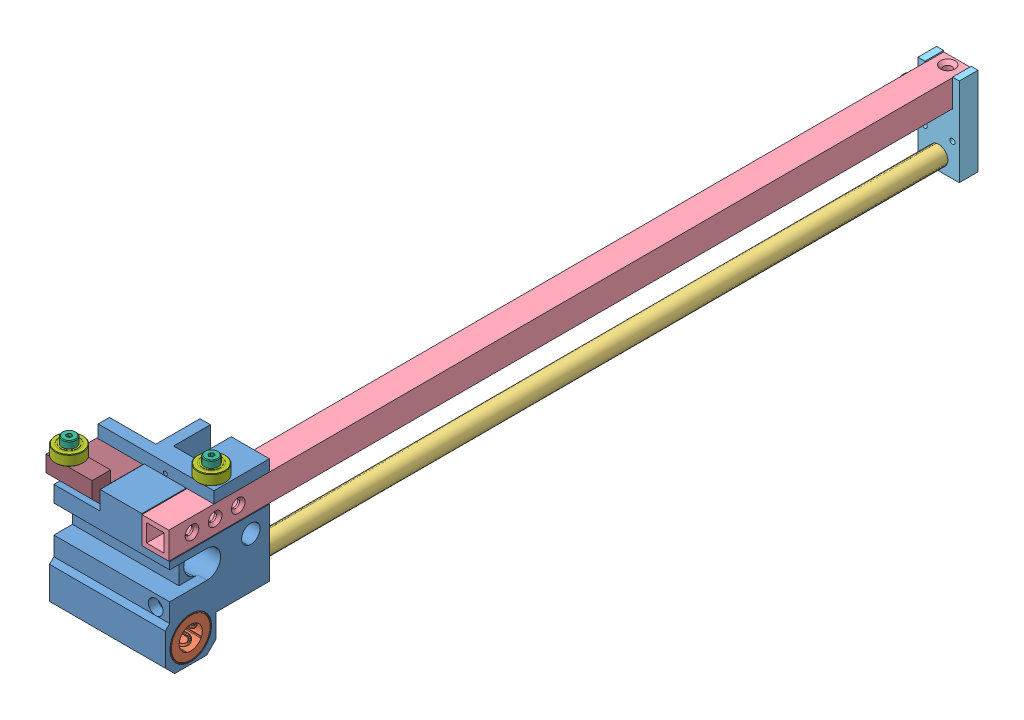
SolidWorks assembly C_Master_01, configuration Default. Lengths in mm.
Overall size (84.09 111.37 565.05).
24 component instances, 18 part files, 39 mates.
Components (placement in the parent):
- C0009-1: C0009 [Default] at origin size (79.5 95.3 71.48)
- 5-8in_ss_6064K590-1: 5-8in_ss_6064K590 [6064K59] at (20.7 0 0) x (0 0.450119 -0.892968) z (1 0 0) size (28.57 28.57 38.1)
- 5-8in_ss_6064K590-2: 5-8in_ss_6064K590 [6064K59] at (-20.7 0 0) x (0 0 -1) z (1 0 0) size (28.57 28.57 38.1)
- C0006-1: C0006 [Default] at (30.16 20.73 -269.66) x (0 0 1) z (0.021318 0.999773 0) size (514 12.7 12.7)
- C0007-1: C0007 [Default] at (29.93 61.68 -536.01) x (0 1 0) z (1 0 0) size (18.46 550.5 18.46)
- C0001-1: C0001 [M5 hole] at (30.16 20.73 -536.01) x (0 -1 0) z (-1 0 0) size (60.5 12.86 28.36)
- Shoulder_1-4x5-16_10-32_94035A532-1: Shoulder_1-4x5-16_10-32_94035A532 [94035A532] at (30.235 87.3775 -23.735) size (9.53 19.28 9.53)
- 1-4x3-4x9-32_2342K184-1: 1-4x3-4x9-32_2342K184 [2342K184] at (30.235 83.8056 -23.735) x (0.973964 0 0.226703) z (0 -1 0) size (19.05 19.05 7.14)
- flanged_10x19x7-1: flanged_10x19x7 [Default] at (-7.8812 41.19 -41.28) size (7 20.5 20.5)
- flanged_10x19x5-1: flanged_10x19x5 [Default] at (13.55 41.19 -41.28) size (5 20.5 20.5)
- Pulley_MoldedAssmC-1: Pulley_MoldedAssmC [Default] at (5.35 41.19 -41.28) x (-1 0 0) z (0 -0.924225 -0.381849) size (26.43 19 19)
  - GT3x18_GPA18GT3060-A-H8-1: GT3x18_GPA18GT3060-A-H8 [Machined] at origin size (11 19 19)
  - Square_Insert-C^Pulley_MoldedAssmC-1: Square_Insert-C^Pulley_MoldedAssmC [Default] at origin size (26.43 11 11) (virtual)
  - SpringPin_1x4_91611A065-1: SpringPin_1x4_91611A065 [Default] at (0 5.16 0) x (0 -1 0) z (0.072118 0 0.997396) size (4.02 1.01 1)
- C0002-1: C0002 [Default] at (-23.86 79.48 13.615) x (0 0 -1) z (0 1 0) size (34.89 31.6 21.47)
- Shoulder_1-4x5-16_10-32_94035A532-2: Shoulder_1-4x5-16_10-32_94035A532 [94035A532] at (-30.12 87.4175 13.615) size (9.53 19.28 9.53)
- 1-4x3-4x9-32_2342K184-2: 1-4x3-4x9-32_2342K184 [2342K184] at (-30.12 83.8456 13.615) x (1 0 0) z (0 1 0) size (19.05 19.05 7.14)
- AFDF11_5_15-1: AFDF11_5_15 [Default] at (5.35 41.345 -529.58) x (1 0 0) z (0 0.860488 -0.50947) size (11.5 18 18)
  - AFDF11_5_15_idler-1: AFDF11_5_15_idler [Default] at origin size (11.5 18 18)
  - B675ZZ-1: B675ZZ [Default] at (-3.25 0 0) x (-1 0 0) z (0 0 1) size (2.5 8 8)
  - B675ZZ-2: B675ZZ [Default] at (5.75 0 0) x (-1 0 0) z (0 0 1) size (2.5 8 8)
- Spacer-4-3x6x5mm_al_94669A008-1: Spacer-4-3x6x5mm_al_94669A008 [Drilled Out] at (13.48 41.345 -529.58) x (0 1 0) z (0 0 1) size (6 5 6)
- Flat_M5x20_93395A310-1: Flat_M5x20_93395A310 [93395A310] at (0 41.345 -529.58) x (0 0.155545 0.987829) z (-1 0 0) size (9.86 9.86 20.23)
- Belt^C_Master_01-1: Belt^C_Master_01 [Default] at origin size (5 19.25 507.4) (virtual)
Mates (geometry in assembly coordinates):
- Coincident1: coincident aligned: plane of C0009-1 through (0 0 0) normal (0 1 0); plane of assembly through (0 0 0) normal (0 1 0)
- Coincident2: coincident aligned: plane of C0009-1 through (0 0 0) normal (1 0 0); plane of assembly through (0 0 0) normal (1 0 0)
- Coincident3: coincident aligned: plane of C0009-1 through (0 0 0) normal (0 0 1); plane of assembly through (0 0 0) normal (0 0 1)
- Concentric1: concentric anti-aligned: cylinder of C0009-1 through (-39.75 0 0) axis (1 0 0) radius 14.28; cylinder of 5-8in_ss_6064K590-2 through (-1.65 0 0) axis (-1 0 0) radius 14.2875
- Concentric2: concentric anti-aligned: cylinder of C0009-1 through (-39.75 0 0) axis (1 0 0) radius 14.28; cylinder of 5-8in_ss_6064K590-1 through (39.75 0 0) axis (-1 0 0) radius 14.2875
- Coincident4: coincident aligned: plane of C0009-1 through (39.75 1.62 28.5183) normal (1 0 0); plane of 5-8in_ss_6064K590-1 through (39.75 0 0) normal (1 0 0)
- Coincident5: coincident aligned: plane of C0009-1 through (-39.75 1.62 28.5183) normal (-1 0 0); plane of 5-8in_ss_6064K590-2 through (-39.75 0 0) normal (-1 0 0)
- Concentric3: concentric aligned: cylinder of C0009-1 through (30.16 20.73 -12.66) axis (0 0 -1) radius 6.35; cylinder of C0006-1 through (30.16 20.73 -536.9658) axis (0 0 -1) radius 6.35
- Coincident6: coincident anti-aligned: plane of C0009-1 through (30.16 20.73 -12.66) normal (0 0 -1); plane of C0006-1 through (30.0246 14.3814 -12.66) normal (0 0 1)
- Coincident7: coincident anti-aligned: plane of C0009-1 through (20.7 71.51 17.48) normal (1 0 0); plane of C0007-1 through (20.7 52.45 14.49) normal (-1 0 0)
- Coincident8: coincident anti-aligned: plane of C0009-1 through (39.75 52.45 17.48) normal (0 1 0); plane of C0007-1 through (39.16 52.45 14.49) normal (0 -1 0)
- Coincident9: coincident aligned: plane of C0009-1 through (-39.75 71.51 14.49) normal (0 0 1); plane of C0007-1 through (20.7 52.45 14.49) normal (0 0 1)
- Concentric4: concentric aligned: cylinder of C0006-1 through (30.16 20.73 -536.9658) axis (0 0 -1) radius 6.35; cylinder of C0001-1 through (30.16 20.73 -523.15) axis (0 0 -1) radius 3.56
- Parallel1: parallel anti-aligned: plane of C0007-1 through (20.7 52.45 14.49) normal (-1 0 0); plane of C0001-1 through (20.8 52.45 -523.15) normal (1 0 0)
- Coincident11: coincident aligned: plane of C0007-1 through (20.7 52.45 -536.01) normal (0 0 -1); plane of C0001-1 through (39.69 52.45 -536.01) normal (0 0 -1)
- Concentric7: concentric anti-aligned: cylinder of Shoulder_1-4x5-16_10-32_94035A532-1 through (30.235 79.44 -23.735) axis (0 1 0) radius 3.175; cylinder of 1-4x3-4x9-32_2342K184-1 through (30.235 80.2338 -23.735) axis (0 -1 0) radius 9.525
- Concentric8: concentric aligned: cylinder of C0009-1 through (30.235 -15.861 -23.735) axis (0 1 0) radius 1.975; cylinder of Shoulder_1-4x5-16_10-32_94035A532-1 through (30.235 79.44 -23.735) axis (0 1 0) radius 3.175
- Coincident13: coincident anti-aligned: plane of C0009-1 through (-39.75 79.44 -54) normal (0 1 0); plane of Shoulder_1-4x5-16_10-32_94035A532-1 through (30.235 79.44 -23.735) normal (0 -1 0)
- Coincident14: coincident anti-aligned: plane of Shoulder_1-4x5-16_10-32_94035A532-1 through (30.235 87.3775 -23.735) normal (0 -1 0); plane of 1-4x3-4x9-32_2342K184-1 through (29.4342 87.3775 -20.2948) normal (0 1 0)
- Concentric10: concentric aligned: cylinder of C0009-1 through (17.5188 41.19 -41.28) axis (-1 0 0) radius 9.525; cylinder of flanged_10x19x7-1 through (-7.8812 41.19 -41.28) axis (-1 0 0) radius 9.5
- Coincident17: coincident anti-aligned: plane of C0009-1 through (-7.8812 79.44 -54) normal (-1 0 0); plane of flanged_10x19x7-1 through (-7.8812 51.44 -41.28) normal (1 0 0)
- Coincident18: coincident anti-aligned: plane of C0009-1 through (13.55 79.44 -54) normal (-1 0 0); plane of flanged_10x19x5-1 through (13.55 51.44 -41.28) normal (1 0 0)
- Concentric13: concentric aligned: cylinder of C0009-1 through (17.5188 41.19 -41.28) axis (-1 0 0) radius 9.525; cylinder of flanged_10x19x5-1 through (13.55 41.19 -41.28) axis (-1 0 0) radius 9.5
- Coincident19: coincident anti-aligned: plane of flanged_10x19x5-1 through (12.35 47.94 -41.28) normal (-1 0 0); plane of Pulley_MoldedAssmC-1/Square_Insert-C^Pulley_MoldedAssmC-1 through (12.35 43.2902 -46.3632) normal (1 0 0)
- Concentric14: concentric anti-aligned: cylinder of flanged_10x19x5-1 through (13.55 41.19 -41.28) axis (-1 0 0) radius 5; cylinder of Pulley_MoldedAssmC-1/Square_Insert-C^Pulley_MoldedAssmC-1 through (5.35 41.19 -41.28) axis (1 0 0) radius 5
- Concentric15: concentric aligned: cylinder of C0009-1 through (-15.95 65.2 17.48) axis (0 0 -1) radius 2.695; cylinder of C0002-1 through (-15.95 65.2 1.29) axis (0 0 -1) radius 2
- Parallel2: parallel aligned: plane of C0009-1 through (-39.75 1.62 28.5183) normal (-1 0 0); plane of C0002-1 through (-39.66 79.48 19.98) normal (-1 0 0)
- Distance1: distance = 1 mm anti-aligned: plane of C0002-1 through (-8.06 71.65 -14.91) normal (0 0 -1); plane of C0009-1 through (-39.75 79.44 -15.91) normal (0 0 1)
- Coincident22: coincident anti-aligned: plane of C0002-1 through (-8.06 79.48 19.98) normal (0 1 0); plane of Shoulder_1-4x5-16_10-32_94035A532-2 through (-30.12 79.48 13.615) normal (0 -1 0)
- Concentric16: concentric aligned: cylinder of C0002-1 through (-30.12 73.33 13.615) axis (0 1 0) radius 1.99; cylinder of Shoulder_1-4x5-16_10-32_94035A532-2 through (-30.12 79.48 13.615) axis (0 1 0) radius 3.175
- Concentric17: concentric aligned: cylinder of Shoulder_1-4x5-16_10-32_94035A532-2 through (-30.12 79.48 13.615) axis (0 1 0) radius 3.175; cylinder of 1-4x3-4x9-32_2342K184-2 through (-30.12 87.4175 13.615) axis (0 1 0) radius 3.175
- Coincident23: coincident anti-aligned: plane of Shoulder_1-4x5-16_10-32_94035A532-2 through (-30.12 87.4175 13.615) normal (0 -1 0); plane of 1-4x3-4x9-32_2342K184-2 through (-30.12 87.4175 7.7884) normal (0 1 0)
- Concentric18: concentric anti-aligned: cylinder of AFDF11_5_15-1/AFDF11_5_15_idler-1 through (11.1 41.345 -529.58) axis (-1 0 0) radius 7.5; circle of assembly
- Coincident24: coincident aligned: plane of AFDF11_5_15-1/AFDF11_5_15_idler-1; plane of assembly through (5.35 0 0) normal (1 0 0)
- Coincident25: coincident anti-aligned: plane of C0001-1 through (15.98 71.79 -523.15) normal (-1 0 0); plane of Spacer-4-3x6x5mm_al_94669A008-1 through (15.98 43.495 -529.58) normal (1 0 0)
- Concentric19: concentric anti-aligned: cylinder of AFDF11_5_15-1/B675ZZ-1 through (-0.3 41.345 -529.58) axis (1 0 0) radius 2.5; cylinder of Spacer-4-3x6x5mm_al_94669A008-1 through (3.5938 41.345 -529.58) axis (-1 0 0) radius 3
- Concentric20: concentric anti-aligned: cylinder of AFDF11_5_15-1/B675ZZ-1 through (-0.3 41.345 -529.58) axis (1 0 0) radius 2.5; circle of Flat_M5x20_93395A310-1
- Coincident26: coincident: circle of AFDF11_5_15-1/B675ZZ-1; cone of Flat_M5x20_93395A310-1 through (-2.8 41.345 -529.58) axis (1 0 0); unknown of C0007-1; unknown of C0007-1; unknown of C0007-1
- PLANE1: unknown = 27.1379 mm: plane of ? through (1.7 43.4811 -46.8253) normal (1 0 0); plane of ? through (9 43.4811 -46.8253) normal (-1 0 0)
